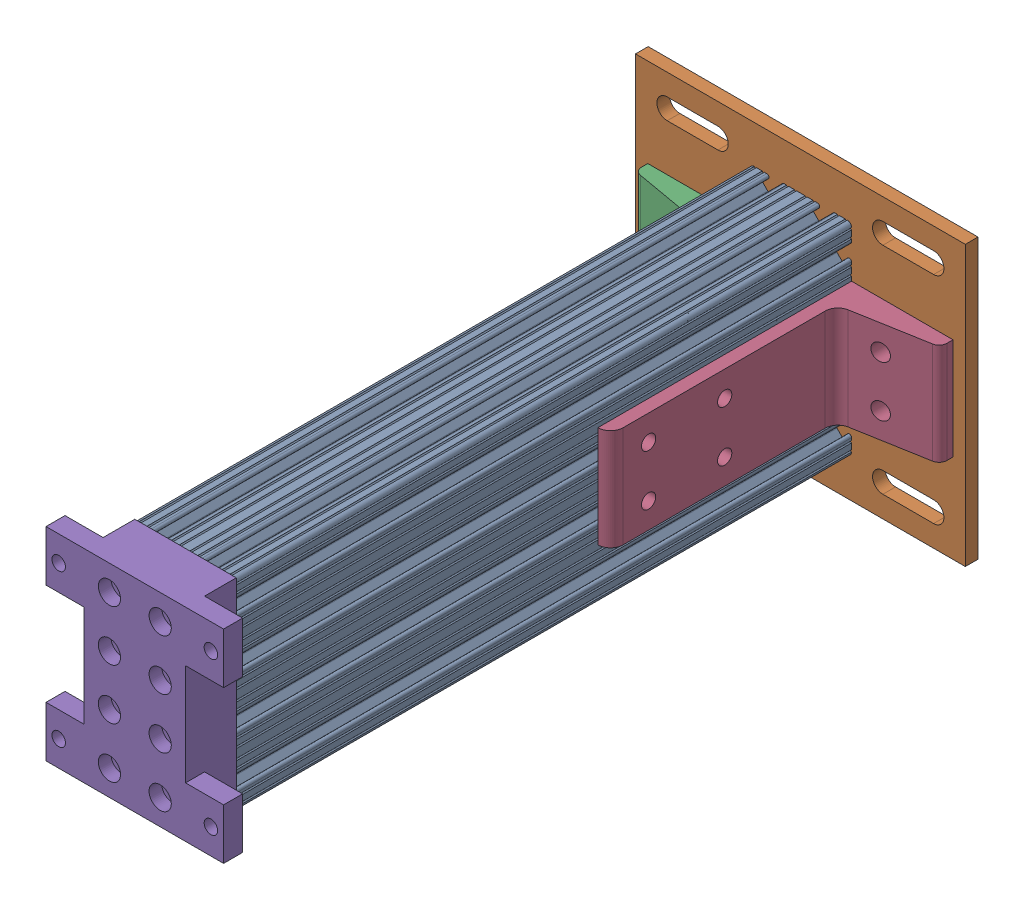
SolidWorks assembly Mirrorbreadboard support leg assembly4, configuration Default. Lengths in mm.
Overall size (165.1 139.7 339.72).
6 component instances, 4 part files, 6 mates.
Components (placement in the parent):
- Mirror8020-2040 leg for breadboard support-1: Mirror8020-2040 leg for breadboard support [Default] at (-48.9055 -77.0614 -78.1612) size (50.8 101.6 307.98)
- Mirror8020-2387-DEFAULT4-1: Mirror8020-2387-DEFAULT4 [Default] at (-34.9863 -22.6888 -91.8816) x (0 1 0) z (1 0 0) size (139.7 133.35 165.1)
  - Mirror8020-2387-DEFAULT_238708-1: Mirror8020-2387-DEFAULT_238708 [Default] at (-67.1549 7.3704 -27.8119) size (139.7 6.35 165.1)
  - Mirror8020-2387-DEFAULT_238509-1: Mirror8020-2387-DEFAULT_238509 [Default] at (9.1264 0.0214 -49.7635) x (0 0 -1) z (1 0 0) size (50.8 127 50.8)
  - Mirror8020-2387-DEFAULT_238509-2: Mirror8020-2387-DEFAULT_238509 [Default] at (-41.6736 0.0214 46.9187) x (0 0 1) z (-1 0 0) size (50.8 127 50.8)
- Mirrorbreadboard support leg top bracket-1: Mirrorbreadboard support leg top bracket [Default] at (-61.6055 -89.7614 229.8138) x (0 1 0) z (1 0 0) size (101.6 25.4 88.9)
Mates (geometry in assembly coordinates):
- Coincident1: coincident anti-aligned: plane of Mirror8020-2040 leg for breadboard support-1 through (-61.6055 -36.3198 -78.1612) normal (0 0 -1); plane of Mirror8020-2387-DEFAULT4-1/Mirror8020-2387-DEFAULT_238708-1 through (-36.4088 -207.3239 -78.1612) normal (0 0 1)
- Coincident2: coincident anti-aligned: plane of Mirror8020-2040 leg for breadboard support-1 through (-10.8056 -41.095 229.8138) normal (1 0 0); plane of Mirror8020-2387-DEFAULT4-1/Mirror8020-2387-DEFAULT_238509-2 through (-10.8056 -13.5624 -150.9329) normal (-1 0 0)
- Distance1: distance = 19.05 mm aligned: plane of Mirror8020-2387-DEFAULT4-1/Mirror8020-2387-DEFAULT_238708-1 through (-36.4088 -108.8114 -78.1612) normal (0 -1 0); plane of Mirror8020-2040 leg for breadboard support-1 through (-38.3391 -89.7614 229.8138) normal (0 -1 0)
- Coincident3: coincident anti-aligned: plane of Mirror8020-2040 leg for breadboard support-1 through (-61.6055 -36.3198 229.8138) normal (0 0 1); plane of Mirrorbreadboard support leg top bracket-1 through (-10.8055 -89.7614 229.8138) normal (0 0 -1)
- Concentric1: concentric anti-aligned: circle of Mirror8020-2040 leg for breadboard support-1; circle of Mirrorbreadboard support leg top bracket-1
- Concentric2: concentric anti-aligned: circle of Mirror8020-2040 leg for breadboard support-1; circle of Mirrorbreadboard support leg top bracket-1
